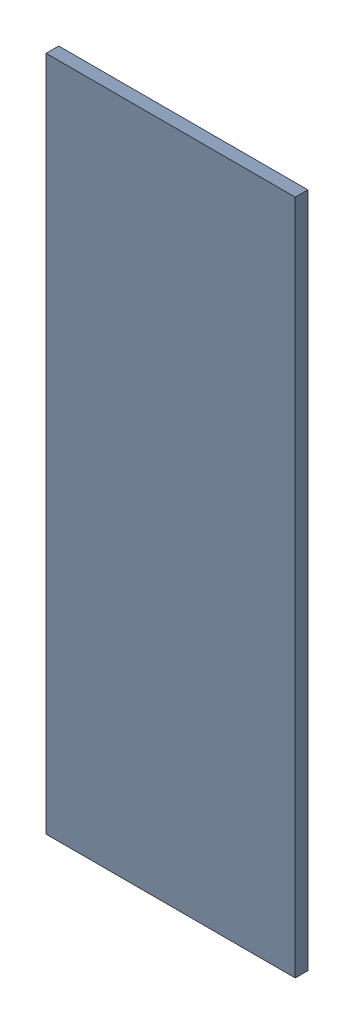
SolidWorks assembly Pad RAK4600-15(18.725mm,8.691mm) on Top Layer, configuration Predeterminado. Lengths in mm.
Overall size (0.7 1.9 0.04).
2 component instances, 1 part files, 0 mates.
Components (placement in the parent):
- Pad RAK4600-15(18.725mm,8.691mm) on Top Layer-1-1: Pad RAK4600-15(18.725mm,8.691mm) on Top Layer-1 [Predeterminado] at (-68.317 -44.187 -0.0457) size (0.7 1.9 0.04)
  - Pad RAK4600-15(18.725mm,8.691mm) on Top Layer-Part-1-1: Pad RAK4600-15(18.725mm,8.691mm) on Top Layer-Part-1 [Predeterminado] at origin size (0.7 1.9 0.04)
